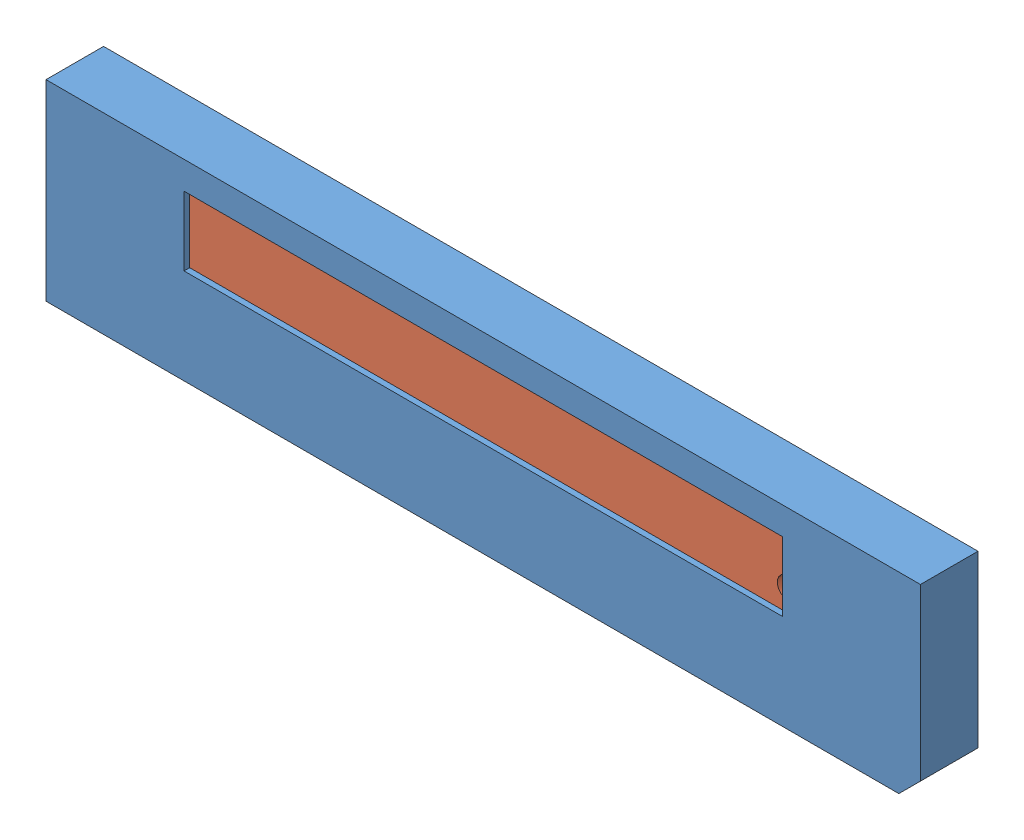
SolidWorks assembly LVF, configuration По умолчанию. Lengths in mm.
Overall size (81.1 17.8 5.34).
3 component instances, 3 part files, 2 mates.
Components (placement in the parent):
- LVF body-1: LVF body [По умолчанию] at origin size (81.1 17.8 5.34)
- Деталь4^LVF-1: Деталь4^LVF [По умолчанию] at origin (virtual)
- LVF glass-1: LVF glass [По умолчанию] at (12.8 8.8339 2.8191) size (56.5 6.41 2)
Mates (geometry in assembly coordinates):
- Совпадение1: coincident: plane of LVF body-1 through (68.3 8.8339 0) normal (-1 0 0); plane of LVF glass-1 through (68.3 -6.41 4.8191) normal (1 0 0)
- Совпадение2: coincident anti-aligned: plane of LVF body-1 through (12.8 8.8339 0) normal (0 1 0); plane of LVF glass-1 through (12.8 8.8339 4.8191) normal (0 -1 0)
